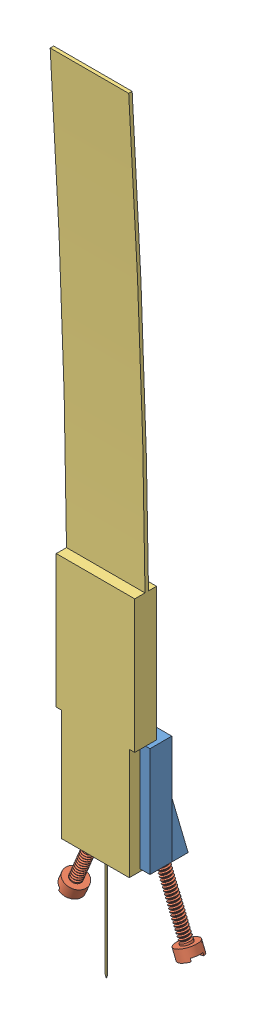
SolidWorks assembly Assem_implant_only, configuration Default. Lengths in mm.
Overall size (13.34 72.83 5.22).
4 component instances, 3 part files, 5 mates.
Components (placement in the parent):
- neuropixel_holder-1: neuropixel_holder [Standard] at (-45.1661 19.9461 11.6436) size (8 10.96 3.5)
- screw-1: screw [Standard] at (-42.3825 13.2976 11.3936) x (-0.382683 -0.92388 0) z (0.647685 -0.26828 0.713113) size (11.14 2 2)
- screw-3: screw [Standard] at (-39.8661 13.1981 11.3936) x (0.382683 -0.92388 0) z (-0.195556 -0.081002 0.977342) size (11.14 2 2)
- Neuropixel 2019-2: Neuropixel 2019 [Default] at (-41.1661 26.0461 14.6436) x (-1 0 0) z (0 -1 0) size (7.2 2.55 72.83)
Mates (geometry in assembly coordinates):
- Screw1: screw = 1: cylinder of neuropixel_holder-1 through (-43.975 9.4528 11.3936) axis (-0.382683 -0.92388 0) radius 0.6; cylinder of screw-1 through (-46.592 3.1349 11.3936) axis (0.382683 0.92388 0) radius 1
- Concentric1: concentric: cylinder of neuropixel_holder-1 through (-38.3209 9.4678 11.3936) axis (0.382683 -0.92388 0) radius 0.5; cylinder of screw-3 through (-35.6566 3.0354 11.3936) axis (-0.382683 0.92388 0) radius 1
- Coincident7: coincident: plane of neuropixel_holder-1 through (-45.1661 19.9461 12.6436) normal (0 0 1); plane of Neuropixel 2019-2 through (-41.1661 26.0461 12.6436) normal (0 0 -1)
- Coincident8: coincident: plane of neuropixel_holder-1 through (-38.0661 19.9461 12.6436) normal (-1 0 0); plane of Neuropixel 2019-2 through (-38.0661 26.0461 12.6436) normal (1 0 0)
- Coincident11: coincident: plane of neuropixel_holder-1 through (-45.1661 19.9461 13.6436) normal (0 1 0); plane of Neuropixel 2019-2 through (-41.1661 19.9461 12.6436) normal (0 -1 0)
